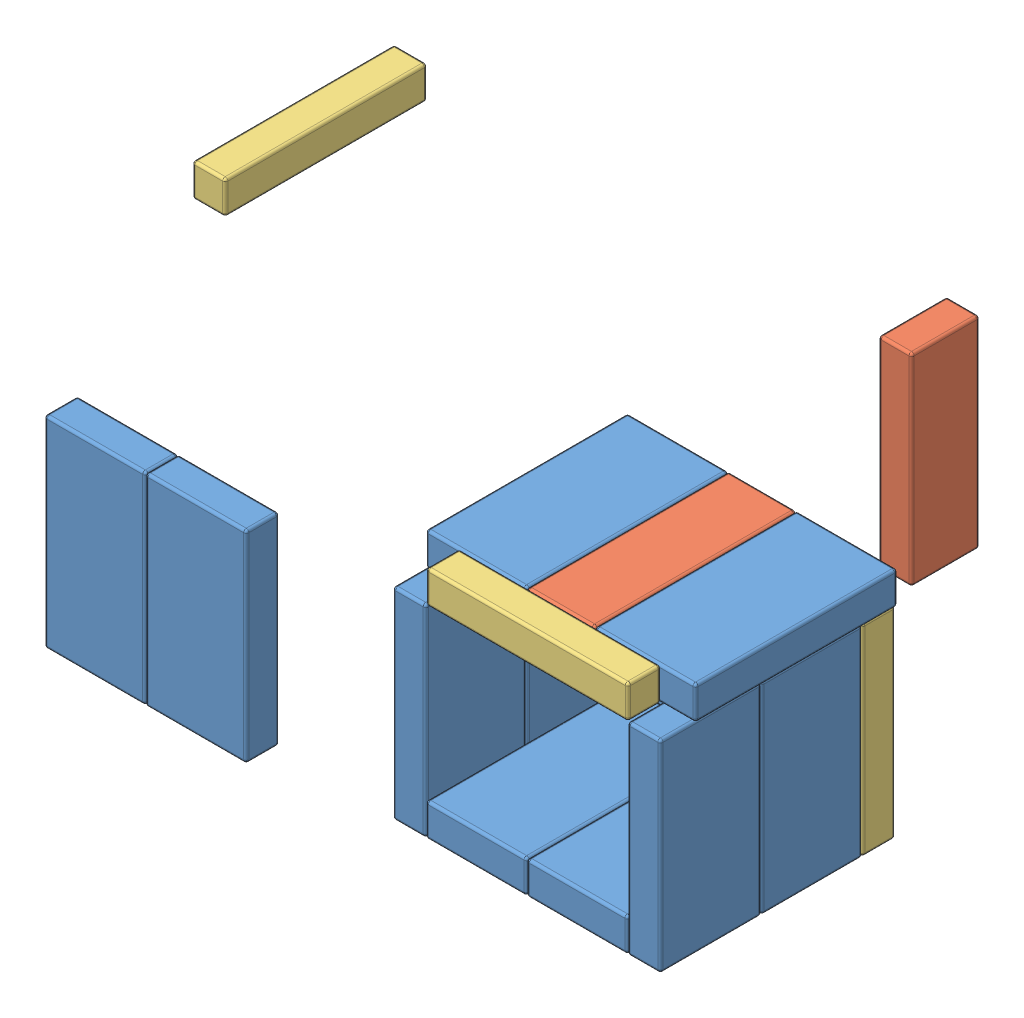
SolidWorks assembly Assem1, configuration Default. Lengths in mm.
Overall size (669.72 402.18 506.95).
18 component instances, 3 part files, 43 mates.
Components (placement in the parent):
- K26 Half-1: K26 Half [Default] at origin size (115 37.5 230)
- K26 Half-3: K26 Half [Default] at (115 96.25 -133.75) x (1 0 0) z (0 1 0) size (115 37.5 230)
- K26 Half-4: K26 Half [Default] at (115 0 0) size (115 37.5 230)
- K26 Half-5: K26 Half [Default] at (191.25 96.25 -57.5) x (0 0 1) z (0 -1 0) size (115 37.5 230)
- K26 Half-6: K26 Half [Default] at (0 96.25 -133.75) x (1 0 0) z (0 -1 0) size (115 37.5 230)
- K26 Half-7: K26 Half [Default] at (-76.25 96.25 -57.5) x (0 0 -1) z (0 -1 0) size (115 37.5 230)
- K26 Half-8: K26 Half [Default] at (155 230 -37.5) size (115 37.5 230)
- K26 Half-9: K26 Half [Default] at (-37.5 230 -37.5) size (115 37.5 230)
- K26 Half-10: K26 Half [Default] at (-282.0174 104.661 133.75) x (-1 0 0) z (0 1 0) size (115 37.5 230)
- K26 Half-11: K26 Half [Default] at (-397.0174 104.661 133.75) x (-1 0 0) z (0 1 0) size (115 37.5 230)
- K26 Door Cut-1: K26 Door Cut [Default] at (58.75 230 -37.5) size (77.5 37.5 230)
- K26 Door Cut-2: K26 Door Cut [Default] at (85.4824 228.789 -315.697) x (0 0 1) z (0 -1 0) size (77.5 37.5 230)
- K26 Door Leftover-1: K26 Door Leftover [Default] at (191.25 96.25 -133.75) x (1 0 0) z (0 1 0) size (37.5 37.5 230)
- K26 Door Leftover-2: K26 Door Leftover [Default] at (-76.25 96.25 -133.75) x (-1 0 0) z (0 -1 0) size (37.5 37.5 230)
- K26 Half-12: K26 Half [Default] at (191.25 96.25 57.5) x (0 0 -1) z (0 -1 0) size (115 37.5 230)
- K26 Half-13: K26 Half [Default] at (-76.25 96.25 57.5) x (0 0 -1) z (0 1 0) size (115 37.5 230)
- K26 Door Leftover-3: K26 Door Leftover [Default] at (57.982 230 96.25) x (0 0 -1) z (1 0 0) size (37.5 37.5 230)
- K26 Door Leftover-4: K26 Door Leftover [Default] at (-438.473 364.6813 -133.7676) size (37.5 37.5 230)
Mates (geometry in assembly coordinates):
- Coincident47: coincident aligned: plane of K26 Half-1 through (-57.5 -18.75 115) normal (0 -1 0); plane of K26 Half-6 through (0 -18.75 -133.75) normal (0 -1 0)
- Coincident48: coincident aligned: plane of K26 Half-1 through (-57.5 18.75 115) normal (-1 0 0); plane of K26 Half-6 through (-57.5 -18.75 -115) normal (-1 0 0)
- Coincident49: coincident anti-aligned: plane of K26 Half-1 through (0 0 -115) normal (0 0 -1); plane of K26 Half-6 through (-57.5 -18.75 -115) normal (0 0 1)
- Coincident50: coincident anti-aligned: plane of K26 Half-1 through (57.5 18.75 115) normal (1 0 0); plane of K26 Half-4 through (57.5 18.75 115) normal (-1 0 0)
- Coincident51: coincident aligned: plane of K26 Half-1 through (-57.5 -18.75 115) normal (0 -1 0); plane of K26 Half-4 through (57.5 -18.75 115) normal (0 -1 0)
- Coincident52: coincident aligned: plane of K26 Half-1 through (0 0 -115) normal (0 0 -1); plane of K26 Half-4 through (115 0 -115) normal (0 0 -1)
- Coincident53: coincident anti-aligned: plane of K26 Half-3 through (57.5 211.25 -152.5) normal (-1 0 0); plane of K26 Half-6 through (57.5 -18.75 -115) normal (1 0 0)
- Coincident54: coincident anti-aligned: plane of K26 Half-3 through (57.5 211.25 -115) normal (0 0 1); plane of K26 Half-4 through (115 0 -115) normal (0 0 -1)
- Coincident55: coincident aligned: plane of K26 Half-3 through (115 -18.75 -133.75) normal (0 -1 0); plane of K26 Half-4 through (57.5 -18.75 115) normal (0 -1 0)
- Coincident56: coincident anti-aligned: plane of K26 Half-1 through (-57.5 18.75 115) normal (-1 0 0); plane of K26 Half-7 through (-57.5 -18.75 0) normal (1 0 0)
- Coincident57: coincident aligned: plane of K26 Half-1 through (-57.5 -18.75 115) normal (0 -1 0); plane of K26 Half-7 through (-76.25 -18.75 -57.5) normal (0 -1 0)
- Coincident58: coincident anti-aligned: plane of K26 Half-1 through (-57.5 18.75 115) normal (-1 0 0); plane of K26 Half-13 through (-57.5 211.25 115) normal (1 0 0)
- Coincident59: coincident aligned: plane of K26 Half-1 through (-57.5 -18.75 115) normal (0 -1 0); plane of K26 Half-13 through (-76.25 -18.75 57.5) normal (0 -1 0)
- Coincident60: coincident anti-aligned: plane of K26 Half-7 through (-57.5 -18.75 0) normal (0 0 1); plane of K26 Half-13 through (-95 211.25 0) normal (0 0 -1)
- Coincident62: coincident aligned: plane of K26 Half-1 through (-57.5 -18.75 115) normal (0 -1 0); plane of K26 Door Leftover-2 through (-76.25 -18.75 -133.75) normal (0 -1 0)
- Coincident63: coincident anti-aligned: plane of K26 Half-6 through (-57.5 -18.75 -115) normal (-1 0 0); plane of K26 Door Leftover-2 through (-57.5 -18.75 -152.5) normal (1 0 0)
- Coincident64: coincident aligned: plane of K26 Half-6 through (-57.5 -18.75 -152.5) normal (0 0 -1); plane of K26 Door Leftover-2 through (-57.5 -18.75 -152.5) normal (0 0 -1)
- Coincident66: coincident anti-aligned: plane of K26 Half-7 through (-57.5 -18.75 -115) normal (0 0 -1); plane of K26 Door Leftover-2 through (-57.5 -18.75 -115) normal (0 0 1)
- Coincident67: coincident aligned: plane of K26 Half-3 through (115 -18.75 -133.75) normal (0 -1 0); plane of K26 Door Leftover-1 through (191.25 -18.75 -133.75) normal (0 -1 0)
- Coincident68: coincident anti-aligned: plane of K26 Half-3 through (172.5 211.25 -152.5) normal (1 0 0); plane of K26 Door Leftover-1 through (172.5 211.25 -152.5) normal (-1 0 0)
- Coincident69: coincident aligned: plane of K26 Half-3 through (57.5 211.25 -152.5) normal (0 0 -1); plane of K26 Door Leftover-1 through (172.5 211.25 -152.5) normal (0 0 -1)
- Coincident70: coincident anti-aligned: plane of K26 Half-5 through (172.5 -18.75 -115) normal (0 0 -1); plane of K26 Door Leftover-1 through (172.5 211.25 -115) normal (0 0 1)
- Coincident71: coincident aligned: plane of K26 Half-5 through (210 -18.75 -115) normal (1 0 0); plane of K26 Door Leftover-1 through (210 211.25 -152.5) normal (1 0 0)
- Coincident72: coincident aligned: plane of K26 Half-4 through (57.5 -18.75 115) normal (0 -1 0); plane of K26 Half-5 through (191.25 -18.75 -57.5) normal (0 -1 0)
- Coincident73: coincident aligned: plane of K26 Half-4 through (57.5 -18.75 115) normal (0 -1 0); plane of K26 Half-12 through (191.25 -18.75 57.5) normal (0 -1 0)
- Coincident74: coincident anti-aligned: plane of K26 Half-4 through (172.5 18.75 115) normal (1 0 0); plane of K26 Half-12 through (172.5 -18.75 115) normal (-1 0 0)
- Coincident75: coincident anti-aligned: plane of K26 Half-5 through (172.5 -18.75 0) normal (0 0 1); plane of K26 Half-12 through (210 -18.75 0) normal (0 0 -1)
- Coincident77: coincident anti-aligned: plane of K26 Half-8 through (97.5 248.75 77.5) normal (-1 0 0); plane of K26 Door Cut-1 through (97.5 248.75 77.5) normal (1 0 0)
- Coincident78: coincident aligned: plane of K26 Half-8 through (97.5 211.25 77.5) normal (0 -1 0); plane of K26 Door Cut-1 through (20 211.25 77.5) normal (0 -1 0)
- Coincident79: coincident aligned: plane of K26 Half-8 through (155 230 -152.5) normal (0 0 -1); plane of K26 Door Cut-1 through (58.75 230 -152.5) normal (0 0 -1)
- Coincident80: coincident anti-aligned: plane of K26 Half-9 through (20 248.75 77.5) normal (1 0 0); plane of K26 Door Cut-1 through (20 248.75 77.5) normal (-1 0 0)
- Coincident81: coincident aligned: plane of K26 Half-9 through (-37.5 230 77.5) normal (0 0 1); plane of K26 Door Cut-1 through (58.75 230 77.5) normal (0 0 1)
- Coincident82: coincident aligned: plane of K26 Half-9 through (-95 211.25 77.5) normal (0 -1 0); plane of K26 Door Cut-1 through (20 211.25 77.5) normal (0 -1 0)
- Coincident83: coincident anti-aligned: plane of K26 Door Cut-1 through (58.75 230 77.5) normal (0 0 1); plane of K26 Door Leftover-3 through (172.982 248.75 77.5) normal (0 0 -1)
- Coincident84: coincident aligned: plane of K26 Door Cut-1 through (20 211.25 77.5) normal (0 -1 0); plane of K26 Door Leftover-3 through (172.982 211.25 115) normal (0 -1 0)
- Coincident85: coincident aligned: plane of K26 Half-6 through (-57.5 -18.75 -152.5) normal (0 0 -1); plane of K26 Door Cut-1 through (58.75 230 -152.5) normal (0 0 -1)
- Coincident86: coincident anti-aligned: plane of K26 Half-5 through (191.25 211.25 -57.5) normal (0 1 0); plane of K26 Door Cut-1 through (20 211.25 77.5) normal (0 -1 0)
- Coincident87: coincident aligned: plane of K26 Half-7 through (-95 -18.75 0) normal (-1 0 0); plane of K26 Half-9 through (-95 248.75 77.5) normal (-1 0 0)
- Coincident88: coincident anti-aligned: plane of K26 Half-10 through (-339.5174 219.661 152.5) normal (-1 0 0); plane of K26 Half-11 through (-339.5174 219.661 152.5) normal (1 0 0)
- Coincident89: coincident aligned: plane of K26 Half-10 through (-224.5174 219.661 115) normal (0 0 -1); plane of K26 Half-11 through (-339.5174 219.661 115) normal (0 0 -1)
- Coincident90: coincident aligned: plane of K26 Half-10 through (-282.0174 219.661 133.75) normal (0 1 0); plane of K26 Half-11 through (-397.0174 219.661 133.75) normal (0 1 0)
- Coincident91: coincident anti-aligned: plane of K26 Half-10 through (-224.5174 219.661 115) normal (0 0 -1); plane of K26 Half-12 through (210 -18.75 115) normal (0 0 1)
- Parallel4: parallel aligned: plane of K26 Half-11 through (-397.0174 219.661 133.75) normal (0 1 0); plane of K26 Door Cut-1 through (20 248.75 77.5) normal (0 1 0)
